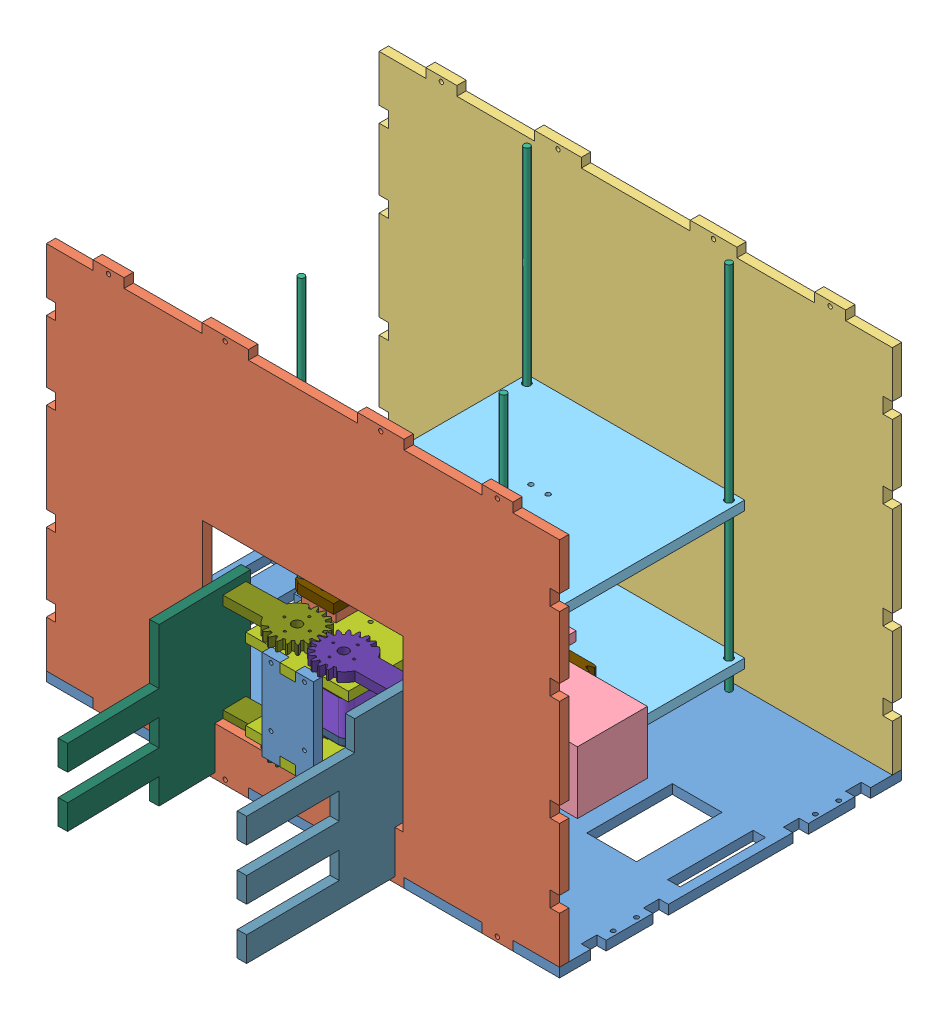
SolidWorks assembly Assemblage Carcasse, configuration Défaut. Lengths in mm.
Overall size (330 250 316.75).
52 component instances, 25 part files, 41 mates.
Components (placement in the parent):
- Carcasse axe XY bas (Bati)-1: Carcasse axe XY bas (Bati) [Défaut] at (-4.3359 -333 21.37) x (1 0 0) z (0 1 0) size (330 220 6)
- Carcasse axe XZ avant-1: Carcasse axe XZ avant [Défaut] at (-4.3359 -208 125.37) size (330 250 6)
- Carcasse axe XZ arrière-1: Carcasse axe XZ arrière [Défaut] at (-4.3359 -208 -88.63) size (330 250 6)
- Carcasse axe YZ gauche-1: Carcasse axe YZ gauche [Défaut] at (154.6641 -208 21.37) size (6 250 220) (hidden)
- Carcasse axe YZ droite-2: Carcasse axe YZ droite [Défaut] at (-169.3359 -208 21.37) size (6 250 220) (hidden)
- Carcasse axe XY haut-1: Carcasse axe XY haut [Défaut] at (-4.3359 -83 21.37) x (1 0 0) z (0 -1 0) size (330 220 6) (hidden)
- Support des Roues-1: Support des Roues [Défaut] at (83.6641 -309.4038 33.9856) x (0 0 1) z (-1 0 0) size (45 40 170)
- Maintient de Pince-1: Maintient de Pince [Défaut] at (1.1641 -221.3379 -5.13) x (0 0 1) z (0 -1 0) size (155 140 6)
- Maintient de Pince-2: Maintient de Pince [Défaut] at (1.1641 -309.3379 -5.13) x (0 0 1) z (0 -1 0) size (155 140 6)
- Tige de maintient axe Z-1: Tige de maintient axe Z [Défaut] at (-69.3359 -327 -77.63) x (1 0 0) z (0 1 0) size (4 4 238)
- Tige de maintient axe Z-2: Tige de maintient axe Z [Défaut] at (60.6641 -89 -77.63) x (1 0 0) z (0 -1 0) size (4 4 238)
- Tige de maintient axe Z-3: Tige de maintient axe Z [Défaut] at (60.6641 -327 67.37) x (1 0 0) z (0 1 0) size (4 4 238)
- Tige de maintient axe Z-4: Tige de maintient axe Z [Défaut] at (-69.3359 -327 67.37) x (1 0 0) z (0 1 0) size (4 4 238)
- Assemblage Pince-1: Assemblage Pince [Défaut] at (-12.7432 -164.3378 92.5531) x (1 0 0) z (0 -1 0) size (124.84 252.86 102.1)
  - Pièce liaison Pignon Bati-1: Pièce liaison Pignon Bati [Défaut] at (6.5323 25.7104 75.0001) size (78 76 6)
  - Pièce liaison Pignon Bati-2: Pièce liaison Pignon Bati [Défaut] at (6.5323 25.7104 133.0001) x (-1 0 0) z (0 0 -1) size (78 76 6)
  - AX-12A-1: AX-12A [Default] at (21.5323 25.7104 96.0001) x (0 -1 0) z (0 0 -1) size (50 32 40.55)
    - AX-12A-01-1: AX-12A-01 [Default] at origin size (48.5 26 22)
    - AX-12A-02-1: AX-12A-02 [Default] at (0 0 13.5) size (50 32 8)
    - AX-12A-03-1: AX-12A-03 [Default] at (0 0 -13.5) x (1 0 0) z (0 0 -1) size (50 32 8)
    - AX-12A-04-1: AX-12A-04 [Default] at (0 0 21) size (22 22 6.7)
    - SetScrew-5: SetScrew [Default] at (33 10.4 14.5) x (0.31498 0.949098 0) z (0 0 -1) size (3.3 3.3 29.44)
    - SetScrew-6: SetScrew [Default] at (-9 9.25 14.5) x (0.31498 0.949098 0) z (0 0 -1) size (3.3 3.3 29.44)
    - SetScrew-7: SetScrew [Default] at (-9 -9.25 14.5) x (-0.958559 0.284893 0) z (0 0 -1) size (3.3 3.3 29.44)
    - SetScrew-8: SetScrew [Default] at (33 -10.4 14.5) x (0.31498 0.949098 0) z (0 0 -1) size (3.3 3.3 29.44)
    - pan head cross recess screw_iso-1: pan head cross recess screw_iso [ISO 7045 - M2.5 x 8 - Z --- 8C] at (0 0 21.6) x (0 0 -1) z (1 0 0) size (10.05 5 5)
  - AX-12A-2: AX-12A [Default] at (-8.4677 25.7104 112.0001) x (0 -1 0) z (0 0 1) size (50 32 40.55)
    - AX-12A-01-1: AX-12A-01 [Default] at origin size (48.5 26 22)
    - AX-12A-02-1: AX-12A-02 [Default] at (0 0 13.5) size (50 32 8)
    - AX-12A-03-1: AX-12A-03 [Default] at (0 0 -13.5) x (1 0 0) z (0 0 -1) size (50 32 8)
    - AX-12A-04-1: AX-12A-04 [Default] at (0 0 21) size (22 22 6.7)
    - SetScrew-5: SetScrew [Default] at (33 10.4 14.5) x (0.31498 0.949098 0) z (0 0 -1) size (3.3 3.3 29.44)
    - SetScrew-6: SetScrew [Default] at (-9 9.25 14.5) x (0.31498 0.949098 0) z (0 0 -1) size (3.3 3.3 29.44)
    - SetScrew-7: SetScrew [Default] at (-9 -9.25 14.5) x (-0.958559 0.284893 0) z (0 0 -1) size (3.3 3.3 29.44)
    - SetScrew-8: SetScrew [Default] at (33 -10.4 14.5) x (0.31498 0.949098 0) z (0 0 -1) size (3.3 3.3 29.44)
    - pan head cross recess screw_iso-1: pan head cross recess screw_iso [ISO 7045 - M2.5 x 8 - Z --- 8C] at (0 0 21.6) x (0 0 -1) z (1 0 0) size (10.05 5 5)
  - Pièce pince facette A-1: Pièce pince facette A [Défaut] at (61.9724 87.5991 124.2676) x (0 0 -1) z (0.999971 -0.007647 0) size (101.1 120 6)
  - Pièce pince facette B-1: Pièce pince facette B [Défaut] at (-53.224 88.1958 106.1676) x (0 0 -1) z (0.999793 -0.020337 0) size (101.1 120 6)
  - Pignon facette A-1: Pignon facette A [ISO - Spur gear 1.5M 20T 20PA 6FW ---S20A75H50L10.0N] at (-8.4677 25.7104 75.0001) x (0 0 -1) z (0.999793 -0.020337 0) size (6 32.71 62.37)
  - Pignon facette A-2: Pignon facette A [ISO - Spur gear 1.5M 20T 20PA 6FW ---S20A75H50L10.0N] at (-8.4677 25.7104 139.0001) x (0 0 -1) z (0.999793 -0.020337 0) size (6 32.71 62.37)
  - Pignon facette B-1: Pignon facette B [ISO - Spur gear 1.5M 20T 20PA 6FW ---S20A75H50L10.0N] at (21.5323 25.7104 69) x (0 0 1) z (-0.988856 -0.148877 0) size (6 32.71 62.94)
  - Pignon facette B-2: Pignon facette B [ISO - Spur gear 1.5M 20T 20PA 6FW ---S20A75H50L10.0N] at (21.5323 25.7104 133.0001) x (0 0 1) z (-0.988856 -0.148877 0) size (6 32.71 62.94)
  - Glissière axe Y-1: Glissière axe Y [ISO - Rack-spur - rectangular 1.5M 20PA 6FW 25PH 150L---SAll] at (-1.9677 8.7104 63.0001) x (0 -1 0) z (0 0 -1) size (126 26.5 6)
  - Glissière axe Y-2: Glissière axe Y [ISO - Rack-spur - rectangular 1.5M 20PA 6FW 25PH 150L---SAll] at (15.0323 8.7104 145) x (0 -1 0) z (0 0 1) size (126 26.5 6)
  - Pièce renfort-1: Pièce renfort [Défaut] at (6.5323 40.7104 97.0001) x (1 0 0) z (0 1 0) size (33 58 6)
  - Pièce renfort-2: Pièce renfort [Défaut] at (45.5323 -12.7896 97.0001) x (0 1 0) z (-1 0 0) size (33 58 6)
  - Pièce renfort-3: Pièce renfort [Défaut] at (-32.4677 -12.7896 97.0001) x (0 -1 0) z (1 0 0) size (33 58 6)
  - Support Surélève cremaillère-1: Support Surélève cremaillère [Défaut] at (30.8337 -8.6826 133.0001) size (22 30 6)
  - Support Surélève cremaillère-2: Support Surélève cremaillère [Défaut] at (-9.1663 -8.6826 69) size (22 30 6)
- Pignon Glissière axe Y et Z-1: Pignon Glissière axe Y et Z [ISO - Spur gear 1.5M 20T 20PA 6FW ---S20A75H50L10.0N] at (-54.7109 -233.3379 37.37) x (0 1 0) z (-0.060543 0 0.998166) size (6 32.71 32.71)
- Renfort pour liaison glissière-1: Renfort pour liaison glissière [Défaut] at (2.2793 -233.3379 26.9671) x (0 0 -1) z (0 1 0) size (110 6 6)
- Renfort pour liaison glissière-2: Renfort pour liaison glissière [Défaut] at (13.2793 -303.3379 7.7729) x (0 0 1) z (0 -1 0) size (110 6 6)
Mates (geometry in assembly coordinates):
- Coïncidente1: coincident anti-aligned: line of Carcasse axe XY bas (Bati)-1 through (-119.3359 -333 131.37) axis (0 1 0); line of Carcasse axe XZ avant-1 through (-119.3359 -327 131.37) axis (0 -1 0)
- Coïncidente2: coincident anti-aligned: line of Carcasse axe XY bas (Bati)-1 through (-119.3359 -333 125.37) axis (-1 0 0); line of Carcasse axe XZ avant-1 through (-139.3359 -333 125.37) axis (1 0 0)
- Coïncidente3: coincident anti-aligned: line of Carcasse axe XY bas (Bati)-1 through (110.6641 -333 -88.63) axis (0 1 0); line of Carcasse axe XZ arrière-1 through (110.6641 -327 -88.63) axis (0 -1 0)
- Coïncidente4: coincident anti-aligned: line of Carcasse axe XY bas (Bati)-1 through (110.6641 -333 -82.63) axis (1 0 0); line of Carcasse axe XZ arrière-1 through (130.6641 -333 -82.63) axis (-1 0 0)
- Coïncidente9: coincident aligned: line of Carcasse axe XZ avant-1 through (154.6641 -119 131.37) axis (0 -1 0); line of Carcasse axe YZ gauche-1 through (154.6641 -119 131.37) axis (0 -1 0)
- Coïncidente10: coincident aligned: line of Carcasse axe XZ avant-1 through (160.6641 -119 125.37) axis (0 0 1); line of Carcasse axe YZ gauche-1 through (160.6641 -119 125.37) axis (0 0 1)
- Coïncidente11: coincident aligned: line of Carcasse axe XZ arrière-1 through (-163.3359 -129 -88.63) axis (0 1 0); line of Carcasse axe YZ droite-2 through (-163.3359 -129 -88.63) axis (0 1 0)
- Coïncidente12: coincident aligned: line of Carcasse axe XZ arrière-1 through (-169.3359 -119 -88.63) axis (0 0 1); line of Carcasse axe YZ droite-2 through (-169.3359 -119 -88.63) axis (0 0 1)
- Coïncidente15: coincident anti-aligned: line of Carcasse axe XZ avant-1 through (130.6641 -83 125.37) axis (-1 0 0); line of Carcasse axe XY haut-1 through (110.6641 -83 125.37) axis (1 0 0)
- Coïncidente16: coincident aligned: line of Carcasse axe XZ avant-1 through (130.6641 -83 125.37) axis (0 0 1); line of Carcasse axe XY haut-1 through (130.6641 -83 125.37) axis (0 0 1)
- Parallèle1: parallel anti-aligned: plane of Carcasse axe XZ arrière-1 through (-4.3359 -208 -82.63) normal (0 0 1); plane of Support des Roues-1 through (-86.3359 -287 -2.13) normal (0 0 -1)
- Parallèle2: parallel anti-aligned: plane of Carcasse axe YZ gauche-1 through (154.6641 -208 21.37) normal (-1 0 0); plane of Support des Roues-1 through (83.6641 -309.4038 33.9856) normal (1 0 0)
- Coïncidente20: coincident anti-aligned: plane of Carcasse axe XY bas (Bati)-1 through (-4.3359 -327 21.37) normal (0 1 0); plane of Support des Roues-1 through (-86.3359 -327 -2.13) normal (0 -1 0)
- Distance1: distance = 11 mm: line of Support des Roues-1 through (83.6641 -327 -2.13) axis (0 0 1); line of Carcasse axe XY bas (Bati)-1 through (94.6641 -327 -7.13) axis (0 0 1)
- Coaxiale1: concentric anti-aligned: cylinder of Maintient de Pince-2 through (-69.3359 -315.3379 -77.63) axis (0 1 0) radius 2.5; cylinder of Tige de maintient axe Z-1 through (-69.3359 -89 -77.63) axis (0 -1 0) radius 2
- Coaxiale3: concentric anti-aligned: cylinder of Maintient de Pince-1 through (-69.3359 -227.3379 -77.63) axis (0 1 0) radius 2.5; cylinder of Tige de maintient axe Z-1 through (-69.3359 -89 -77.63) axis (0 -1 0) radius 2
- Coaxiale4: concentric anti-aligned: circle of Maintient de Pince-2; cylinder of Tige de maintient axe Z-2 through (60.6641 -327 -77.63) axis (0 1 0) radius 2
- Coaxiale5: concentric aligned: cylinder of Maintient de Pince-1 through (60.6641 -227.3379 -77.63) axis (0 1 0) radius 2.5; cylinder of Tige de maintient axe Z-2 through (60.6641 -327 -77.63) axis (0 1 0) radius 2
- Coaxiale6: concentric anti-aligned: cylinder of Maintient de Pince-2 through (60.6641 -315.3379 67.37) axis (0 1 0) radius 2.5; cylinder of Tige de maintient axe Z-3 through (60.6641 -89 67.37) axis (0 -1 0) radius 2
- Coaxiale7: concentric anti-aligned: cylinder of Maintient de Pince-2 through (-69.3359 -315.3379 67.37) axis (0 1 0) radius 2.5; cylinder of Tige de maintient axe Z-4 through (-69.3359 -89 67.37) axis (0 -1 0) radius 2
- Parallèle5: parallel anti-aligned: plane of Carcasse axe XY bas (Bati)-1 through (-4.3359 -327 21.37) normal (0 1 0); plane of Maintient de Pince-2 through (1.1641 -315.3379 -5.13) normal (0 -1 0)
- Coïncidente25: coincident anti-aligned: plane of Carcasse axe XY bas (Bati)-1 through (-4.3359 -327 21.37) normal (0 1 0); plane of Tige de maintient axe Z-1 through (-69.3359 -327 -77.63) normal (0 -1 0)
- Coïncidente26: coincident anti-aligned: plane of Carcasse axe XY bas (Bati)-1 through (-4.3359 -327 21.37) normal (0 1 0); plane of Tige de maintient axe Z-4 through (-69.3359 -327 67.37) normal (0 -1 0)
- Coïncidente27: coincident anti-aligned: plane of Carcasse axe XY bas (Bati)-1 through (-4.3359 -327 21.37) normal (0 1 0); plane of Tige de maintient axe Z-2 through (60.6641 -327 -77.63) normal (0 -1 0)
- Coïncidente28: coincident aligned: plane of Carcasse axe XY bas (Bati)-1 through (-4.3359 -327 21.37) normal (0 1 0); circle of Tige de maintient axe Z-3
- Parallèle6: parallel anti-aligned: plane of Carcasse axe YZ gauche-1 through (154.6641 -208 21.37) normal (-1 0 0); plane of Maintient de Pince-1 through (65.6641 -227.3379 -82.63) normal (1 0 0)
- Distance3: distance = 89 mm anti-aligned: plane of Maintient de Pince-1 through (65.6641 -227.3379 -82.63) normal (1 0 0); plane of Carcasse axe YZ gauche-1 through (154.6641 -208 21.37) normal (-1 0 0)
- Distance4: distance = 5 mm: line of Carcasse axe XY bas (Bati)-1 through (-103.3359 -327 -7.13) axis (-1 0 0); line of Support des Roues-1 through (-86.3359 -327 -2.13) axis (1 0 0)
- Coïncidente32: coincident anti-aligned: plane of Maintient de Pince-1 through (1.1641 -227.3379 -5.13) normal (0 -1 0); plane of Assemblage Pince-1/Glissière axe Y-1 through (-41.2109 -227.3379 101.2635) normal (0 1 0)
- Coïncidente33: coincident anti-aligned: plane of Maintient de Pince-2 through (1.1641 -309.3379 -5.13) normal (0 1 0); plane of Assemblage Pince-1/Glissière axe Y-2 through (28.7891 -309.3379 101.2635) normal (0 -1 0)
- Coaxiale8: concentric anti-aligned: cylinder of Maintient de Pince-1 through (-54.7109 -227.3379 37.37) axis (0 1 0) radius 5; cylinder of Pignon Glissière axe Y et Z-1 through (-54.7109 -183.3378 37.37) axis (0 -1 0) radius 5
- Coïncidente34: coincident anti-aligned: plane of Maintient de Pince-1 through (1.1641 -227.3379 -5.13) normal (0 -1 0); plane of Pignon Glissière axe Y et Z-1 through (-54.7109 -227.3379 37.37) normal (0 1 0)
- Distance6: distance = 35 mm: cylinder of Pignon Glissière axe Y et Z-1 through (-54.7109 -183.3378 37.37) axis (0 -1 0) radius 5; line of Assemblage Pince-1/Glissière axe Y-1 through (-14.7109 -227.3379 101.2635) axis (0 0 -1)
- Coaxiale10: concentric anti-aligned: cylinder of Maintient de Pince-2 through (-11.7109 -309.3379 57.37) axis (0 -1 0) radius 1.5; cylinder of Renfort pour liaison glissière-1 through (-11.7109 -230.3379 57.37) axis (0 1 0) radius 1.5
- Coaxiale11: concentric anti-aligned: cylinder of Maintient de Pince-2 through (-11.7109 -309.3379 -22.63) axis (0 -1 0) radius 1.5; cylinder of Renfort pour liaison glissière-1 through (-11.7109 -230.3379 -22.63) axis (0 1 0) radius 1.5
- Coïncidente38: coincident anti-aligned: plane of Maintient de Pince-1 through (1.1641 -227.3379 -5.13) normal (0 -1 0); plane of Renfort pour liaison glissière-1 through (2.2793 -227.3379 26.9671) normal (0 1 0)
- Parallèle9: parallel anti-aligned: plane of Assemblage Pince-1/Glissière axe Y-1 through (-14.7109 -233.3379 101.2635) normal (1 0 0); plane of Renfort pour liaison glissière-1 through (-14.7109 -227.3379 72.37) normal (-1 0 0)
- Coïncidente40: coincident anti-aligned: plane of Maintient de Pince-2 through (1.1641 -309.3379 -5.13) normal (0 1 0); plane of Renfort pour liaison glissière-2 through (13.2793 -309.3379 7.7729) normal (0 -1 0)
- Coaxiale12: concentric aligned: cylinder of Maintient de Pince-2 through (-0.7109 -309.3379 -22.63) axis (0 -1 0) radius 1.5; cylinder of Renfort pour liaison glissière-2 through (-0.7109 -306.3379 -22.63) axis (0 -1 0) radius 1.5
- Coaxiale13: concentric aligned: cylinder of Maintient de Pince-2 through (-0.7109 -309.3379 57.37) axis (0 -1 0) radius 1.5; cylinder of Renfort pour liaison glissière-2 through (-0.7109 -306.3379 57.37) axis (0 -1 0) radius 1.5
- Coïncidente41: coincident anti-aligned: plane of Carcasse axe XZ arrière-1 through (-4.3359 -208 -82.63) normal (0 0 1); plane of Maintient de Pince-1 through (-74.3359 -227.3379 -82.63) normal (0 0 -1)
